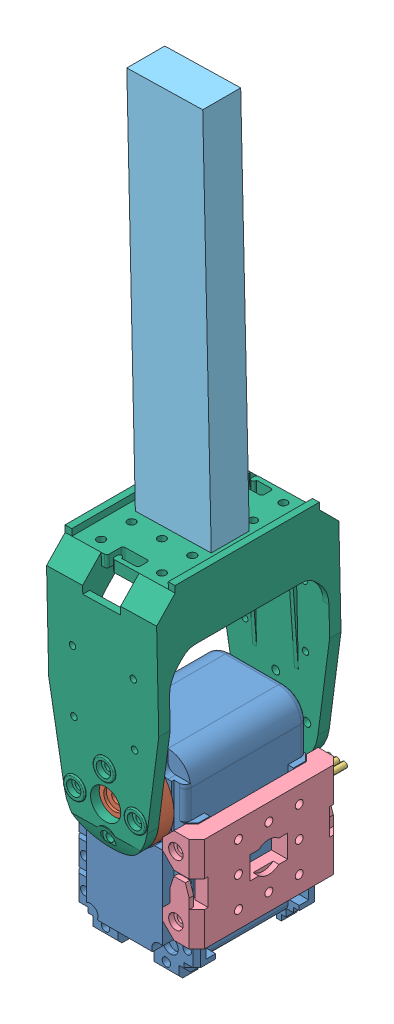
SolidWorks assembly Bras_servo fixation en U, configuration Défaut. Lengths in mm.
Overall size (35 190.69 56.39).
8 component instances, 6 part files, 9 mates.
Components (placement in the parent):
- servomoteur_ax-12-1: servomoteur_ax-12 [Default] at (-3.5987 -0.7426 9.3025) size (32 52.31 53.4)
  - AX-12_modif-1: AX-12_modif [Défaut] at (-2.6768 21.8769 -4.3025) size (32 50.06 38.01)
  - attache_ax-12-1: attache_ax-12 [Default] at (-2.6768 21.8769 12.6975) x (-0.301968 0.953318 0) z (0 0 1) size (22 22 4.7)
  - connecteur_AX-12-1: connecteur_AX-12 [Default] at (6.5732 8.6769 -17.5025) x (-1 0 0) z (0 -1 0) size (8 18.5 4)
  - connecteur_AX-12-2: connecteur_AX-12 [Default] at (-4.0768 8.6769 -17.5025) x (-1 0 0) z (0 -1 0) size (8 18.5 4)
- F3-1: F3 [Défaut] at (12.7216 6.5844 5) x (0 1 0) z (0 0 1) size (25 9 38)
- Bras_pour_servo-1: Bras_pour_servo [Défaut] at (-17.4416 72.8964 10) x (-0.022474 0.999747 0) z (0 0 -1) size (100 20 10)
- F4-1: F4 [Défaut] at (-6.2755 21.1343 5) x (0 0 1) z (-0.022474 0.999747 0) size (49.38 29 64.7)
Mates (geometry in assembly coordinates):
- Coïncidente1: coincident anti-aligned: plane of servomoteur_ax-12-1/AX-12_modif-1 through (-21.8755 -17.2457 21) normal (0 0 1); plane of F3-1 through (9.7216 19.0844 21) normal (0 0 -1)
- Tangent1: tangent: face of servomoteur_ax-12-1/AX-12_modif-1; cylinder of F3-1 through (7.2216 -1.4156 24) axis (0 0 1) radius 1.05
- Tangent2: tangent: face of servomoteur_ax-12-1/AX-12_modif-1; cylinder of F3-1 through (7.2216 14.5844 24) axis (0 0 1) radius 1.05
- Coïncidente2: coincident anti-aligned: plane of servomoteur_ax-12-1/attache_ax-12-1 through (-6.2755 21.1343 26) normal (0 0 1); plane of F4-1 through (-6.2755 21.1343 26) normal (0 0 -1)
- Coaxiale1: concentric aligned: cylinder of servomoteur_ax-12-1/attache_ax-12-1 through (-6.2755 21.1343 21.999) axis (0 0 1) radius 1.4; cylinder of F4-1 through (-6.2755 21.1343 29) axis (0 0 1) radius 4
- Coïncidente3: coincident anti-aligned: plane of Bras_pour_servo-1 through (-17.4416 72.8964 0) normal (0.022474 -0.999747 0); plane of F4-1 through (7.0522 73.447 -19) normal (-0.022474 0.999747 0)
- Parallèle1: parallel aligned: plane of Bras_pour_servo-1 through (2.5534 73.3459 0) normal (0.999747 0.022474 0); plane of F4-1 through (7.7264 43.4546 -19) normal (0.999747 0.022474 0)
- Distance2: distance = 19 mm aligned: plane of Bras_pour_servo-1 through (2.5534 73.3459 0) normal (0 0 -1); plane of F4-1 through (-6.2755 21.1343 -19) normal (0 0 -1)
- Distance3: distance = 2.7 mm anti-aligned: plane of F4-1 through (5.2527 73.4066 -14) normal (-0.999747 -0.022474 0); plane of Bras_pour_servo-1 through (2.5534 73.3459 0) normal (0.999747 0.022474 0)
